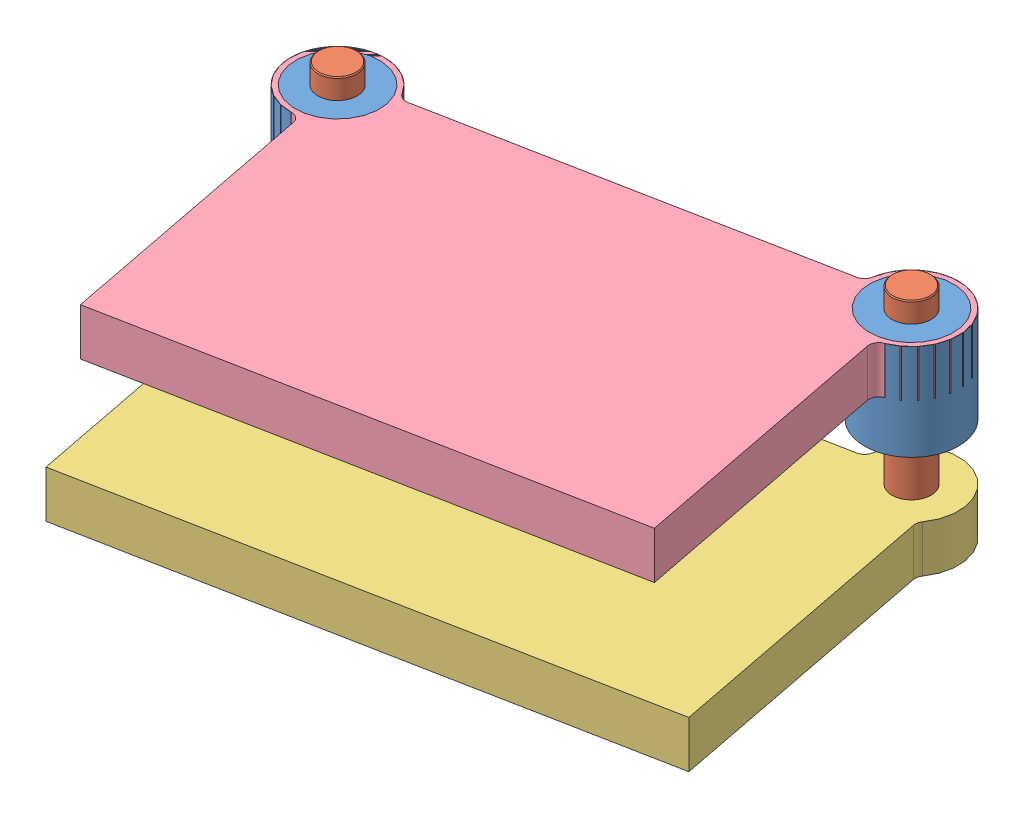
SolidWorks assembly Assem8, configuration Default. Lengths in mm.
Overall size (657.53 224 486.68).
6 component instances, 4 part files, 10 mates.
Components (placement in the parent):
- boosh-1: boosh [Default] at (-492.69 58.3994 143.8285) size (96 98 96)
- boosh-2: boosh [Default] at (-1.8647 58.3994 48.4846) size (96 98 96)
- mile-1: mile [Default] at (-492.69 -47.0395 143.8285) size (40 224 40)
- mile-2: mile [Default] at (-1.8647 -47.0395 48.4846) size (40 224 40)
- kafsake paiini-1: kafsake paiini [Default] at (-183.969 -47.0395 422.0646) x (0.981651 0 -0.190688) z (0.190688 0 0.981651) size (596 48 380)
- kafsake balaii-1: kafsake balaii [Default] at (-183.969 108.3994 422.0646) x (0.981651 0 -0.190688) z (0.190688 0 0.981651) size (596 48 380)
Mates (geometry in assembly coordinates):
- Concentric3: concentric aligned: cylinder of boosh-2 through (-1.8647 156.3994 48.4846) axis (0 -1 0) radius 48; cylinder of kafsake balaii-1 through (-1.8647 156.3994 48.4846) axis (0 -1 0) radius 43
- Coincident4: coincident aligned: plane of boosh-2 through (-1.8647 156.3994 48.4846) normal (0 1 0); plane of kafsake balaii-1 through (-492.69 156.3994 143.8285) normal (0 1 0)
- Concentric4: concentric aligned: cylinder of boosh-1 through (-492.69 156.3994 143.8285) axis (0 -1 0) radius 48; cylinder of kafsake balaii-1 through (-492.69 156.3994 143.8285) axis (0 -1 0) radius 43
- Coincident5: coincident aligned: plane of boosh-1 through (-492.69 156.3994 143.8285) normal (0 1 0); plane of kafsake balaii-1 through (-492.69 156.3994 143.8285) normal (0 1 0)
- Concentric5: concentric aligned: cylinder of mile-1 through (-492.69 176.9605 143.8285) axis (0 -1 0) radius 20; cylinder of kafsake paiini-1 through (-492.69 0.9605 143.8285) axis (0 -1 0) radius 20
- Coincident6: coincident anti-aligned: circle of mile-1; plane of kafsake paiini-1 through (-492.69 -47.0395 143.8285) normal (0 -1 0)
- Concentric6: concentric aligned: cylinder of mile-2 through (-1.8647 176.9605 48.4846) axis (0 -1 0) radius 20; cylinder of kafsake paiini-1 through (-1.8647 0.9605 48.4846) axis (0 -1 0) radius 20
- Coincident7: coincident anti-aligned: circle of mile-2; plane of kafsake paiini-1 through (-492.69 -47.0395 143.8285) normal (0 -1 0)
- Concentric7: concentric aligned: cylinder of boosh-1 through (-492.69 156.3994 143.8285) axis (0 -1 0) radius 20; cylinder of mile-1 through (-492.69 176.9605 143.8285) axis (0 -1 0) radius 20
- Concentric8: concentric aligned: cylinder of boosh-2 through (-1.8647 156.3994 48.4846) axis (0 -1 0) radius 20; cylinder of mile-2 through (-1.8647 176.9605 48.4846) axis (0 -1 0) radius 20
